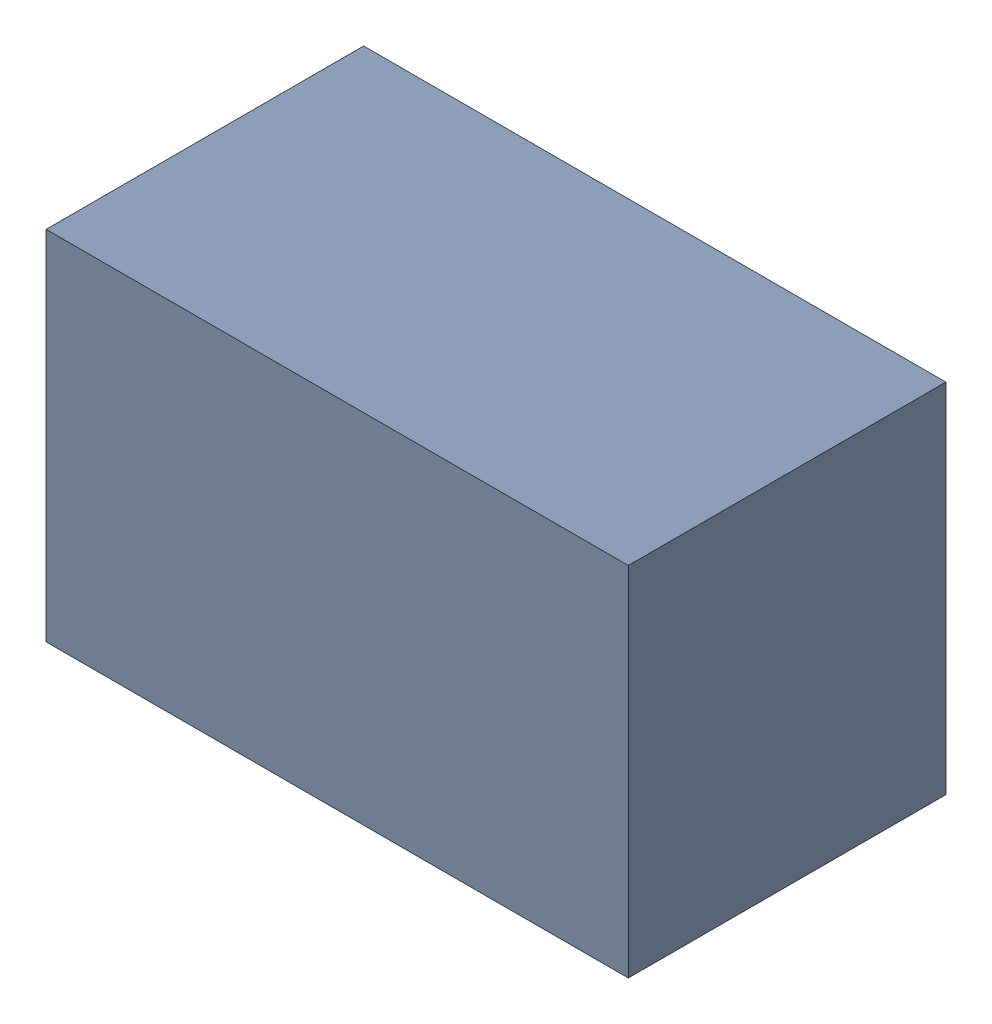
SolidWorks assembly CP2_1, configuration Default. Lengths in mm.
Overall size (2.2 1.35 1.2).
2 component instances, 1 part files, 0 mates.
Components (placement in the parent):
- 407988128-1: 407988128 [Default] at (69.088 4.572 0.0127) size (2.2 1.35 1.2)
  - Extruded_9-1: Extruded_9 [Default] at origin size (2.2 1.35 1.2)
